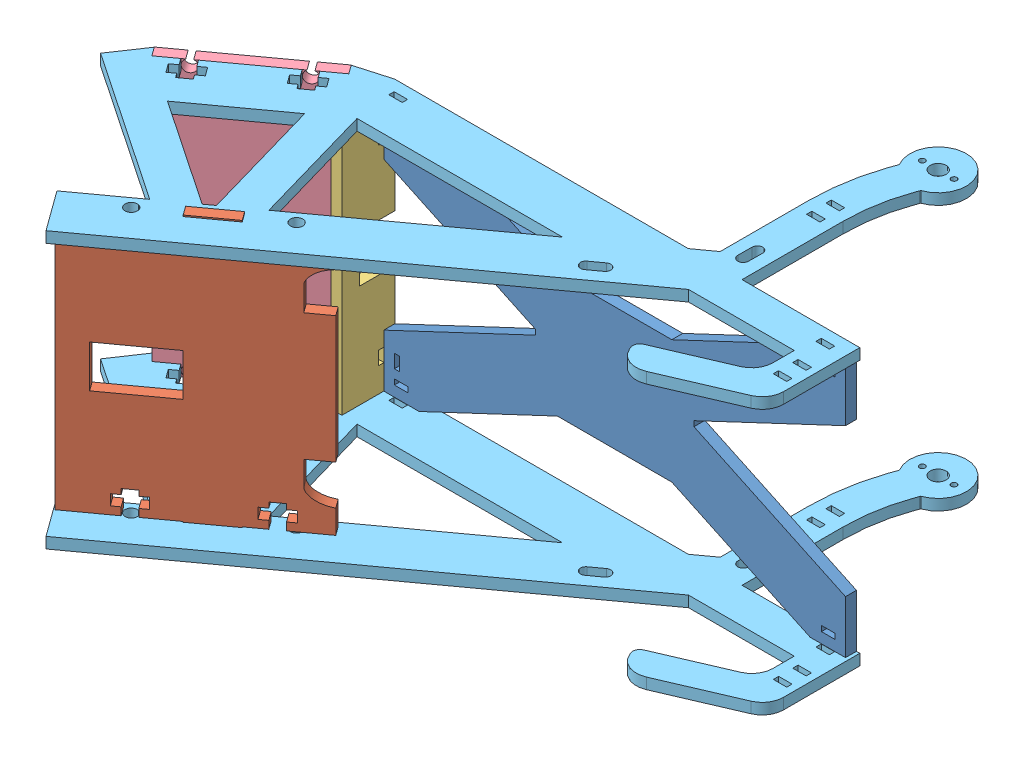
SolidWorks assembly Assem2, configuration 기본. Lengths in mm.
Overall size (206.19 78.61 188.37).
6 component instances, 5 part files, 14 mates.
Components (placement in the parent):
- Face_phone2-1: Face_phone2 [기본] at origin size (131 72 3.11)
- Face_pic-1: Face_pic [기본] at (-70.0168 -12.9961 66.4959) x (0.000005 1 -0.000003) z (0.587785 0 0.809017) size (78.6 57 3.11)
- Face_pole2-1: Face_pole2 [기본] at (-67.8801 -0.3413 7.5914) x (0 1 0) z (1 0 0) size (72 15 3.11)
- Face_spoon2-1: Face_spoon2 [기본] at (-90.7301 -0.3474 14.556) x (0.809017 0 -0.587785) z (0.587785 0 0.809017) size (40 78.22 3.11)
- Side_draft3-1: Side_draft3 [기본] at (-70.612 -36.3556 60.9825) x (0.809017 -0.000006 -0.587785) z (-0.000005 -1 0.000003) size (181.5 100.98 3.11)
- Side_draft3-2: Side_draft3 [기본] at (-70.6118 38.7527 60.9823) x (0.809017 0 -0.587785) z (0 -1 0) size (181.5 100.98 3.11)
Mates (geometry in assembly coordinates):
- Coincident1: coincident anti-aligned: plane of Face_spoon2-1 through (-78.8034 -37.9114 9.7368) normal (0.587785 0 0.809017); plane of Side_draft3-1 through (-97.8109 -39.4671 23.5465) normal (-0.587785 0 -0.809017)
- Coincident2: coincident anti-aligned: plane of Face_spoon2-1 through (-104.9505 -36.3565 28.7337) normal (-0.809017 0.000006 0.587785); plane of Side_draft3-1 through (-77.7518 -39.467 66.1698) normal (0.809017 -0.000006 -0.587785)
- Coincident4: coincident aligned: line of Face_spoon2-1 through (-72.59 -39.4673 5.2225) axis (-0.587785 0 -0.809017); line of Side_draft3-1 through (-72.59 -39.4673 5.2225) axis (-0.587785 0 -0.809017)
- Coincident5: coincident anti-aligned: plane of Face_spoon2-1 through (-78.8034 -37.9114 9.7368) normal (0.587785 0 0.809017); plane of Side_draft3-2 through (-97.8106 35.6412 23.5463) normal (-0.587785 0 -0.809017)
- Coincident6: coincident anti-aligned: plane of Face_spoon2-1 through (-72.5897 35.6427 5.2222) normal (0.809017 0 -0.587785); plane of Side_draft3-2 through (-45.3909 35.6412 42.6582) normal (-0.809017 0 0.587785)
- Coincident7: coincident anti-aligned: line of Face_spoon2-1 through (-104.9504 38.7527 28.7337) axis (-0.587785 0 -0.809017); line of Side_draft3-2 through (-106.7419 38.7527 26.2678) axis (0.587785 0 0.809017)
- Coincident8: coincident anti-aligned: plane of Face_phone2-1 through (-64.7686 -36.3588 3.1115) normal (-1 0 0); plane of Face_pole2-1 through (-64.7686 -0.3413 7.5914) normal (1 0 0)
- Coincident9: coincident anti-aligned: line of Face_phone2-1 through (-64.7686 -21.3588 0) axis (0 -1 0); line of Face_pole2-1 through (-64.7686 -36.3588 0) axis (0 1 0)
- Coincident10: coincident aligned: line of Face_phone2-1 through (-64.7686 -36.3588 3.1115) axis (0 0 -1); line of Face_pole2-1 through (-64.7686 -36.3588 15) axis (0 0 -1)
- Coincident11: coincident anti-aligned: plane of Face_pic-1 through (-39.8011 -27.6732 48.389) normal (0.587785 0 0.809017); plane of Side_draft3-1 through (-65.9557 -39.4671 67.3914) normal (-0.587785 0 -0.809017)
- Coincident12: coincident anti-aligned: line of Face_pic-1 through (-51.304 -39.4672 56.7463) axis (-0.587785 0 -0.809017); line of Side_draft3-1 through (-53.0955 -39.4672 54.2804) axis (0.587785 0 0.809017)
- Coincident13: coincident aligned: line of Face_pic-1 through (-61.0122 -39.4671 63.7997) axis (-0.587785 0 -0.809017); line of Side_draft3-1 through (-61.0122 -39.4671 63.7997) axis (-0.587785 0 -0.809017)
- Coincident14: coincident anti-aligned: line of Face_phone2-1 through (-54.7686 35.6412 0) axis (-1 0 0); line of Side_draft3-2 through (-64.7686 35.6412 0) axis (1 0 0)
- Coincident15: coincident: point of Face_pole2-1; point of Side_draft3-2
